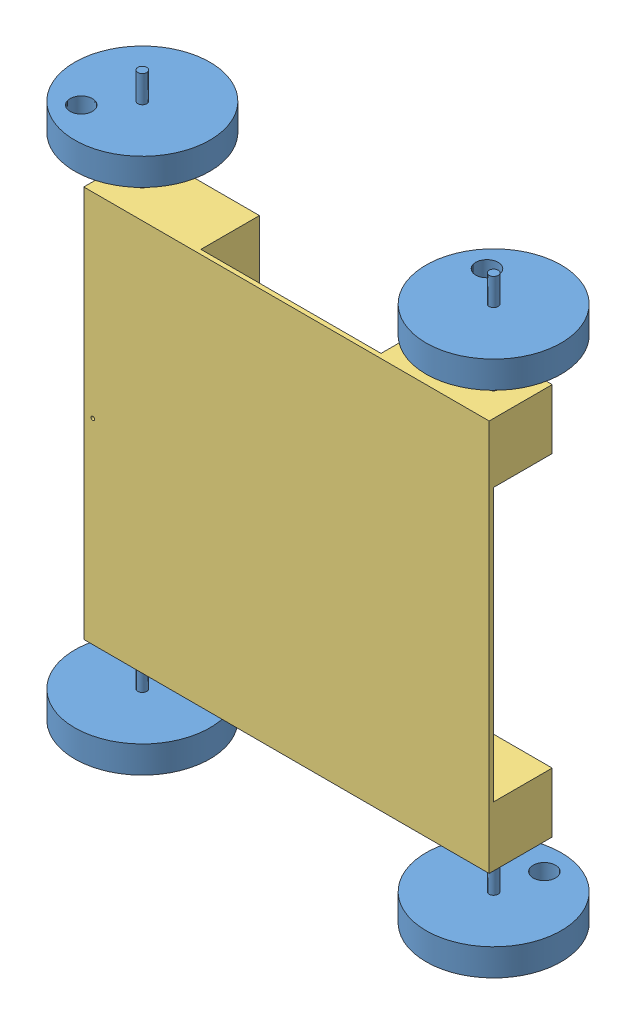
SolidWorks assembly lun, configuration 默认. Lengths in mm.
Overall size (593.07 655 203.07).
9 component instances, 3 part files, 16 mates.
Components (placement in the parent):
- lun-5: lun [默认] at (167.0466 -264.3091 -75) x (-0.881339 0 0.472485) z (0 -1 0) size (150 150 90)
- zhou-6: zhou [默认] at (167.0466 -234.3091 -75) x (1 0 0) z (0 1 0) size (10 10 30)
- zhou-7: zhou [默认] at (-222.9534 -234.3091 -75) x (-0.133084 0 -0.991105) z (0 1 0) size (10 10 30)
- zhou-8: zhou [默认] at (-222.9534 210.6909 -75) x (1 0 0) z (0 1 0) size (10 10 30)
- zhou-9: zhou [默认] at (167.0466 210.6909 -75) x (1 0 0) z (0 1 0) size (10 10 30)
- lun-6: lun [默认] at (167.0466 300.6909 -75) x (0 0 1) z (0 -1 0) size (150 150 90)
- lun-7: lun [默认] at (-222.9534 -264.3091 -75) x (-0.881339 0 0.472485) z (0 -1 0) size (150 150 90)
- SIMPLE DIPAN-2: SIMPLE DIPAN [默认] at (-27.9534 3.1909 -40) x (-1 0 0) z (0 0 -1) size (450 435 70)
- lun-8: lun [默认] at (-222.9534 300.6909 -75) x (1 0 0) z (0 -1 0) size (150 150 90)
Mates (geometry in assembly coordinates):
- 重合24: coincident: plane of zhou-7 through (-222.9534 -234.3091 -75) normal (0 -1 0); plane of lun-7 through (-222.9534 -234.3091 -75) normal (0 1 0)
- 同心17: concentric: cylinder of zhou-7 through (-222.9534 -204.3091 -75) axis (0 -1 0) radius 5; cylinder of lun-7 through (-222.9534 -234.3091 -75) axis (0 -1 0) radius 5
- 重合25: coincident: plane of lun-5 through (167.0466 -234.3091 -75) normal (0 1 0); plane of zhou-6 through (167.0466 -234.3091 -75) normal (0 -1 0)
- 同心18: concentric: cylinder of lun-5 through (167.0466 -234.3091 -75) axis (0 -1 0) radius 5; cylinder of zhou-6 through (167.0466 -204.3091 -75) axis (0 -1 0) radius 5
- 重合26: coincident: plane of zhou-6 through (167.0466 -204.3091 -75) normal (0 1 0); plane of SIMPLE DIPAN-2 through (167.0466 -204.3091 -75) normal (0 -1 0)
- 同心19: concentric: cylinder of zhou-6 through (167.0466 -204.3091 -75) axis (0 -1 0) radius 5; cylinder of SIMPLE DIPAN-2 through (167.0466 -204.3091 -75) axis (0 -1 0) radius 5
- 重合27: coincident: plane of zhou-7 through (-222.9534 -204.3091 -75) normal (0 1 0); plane of SIMPLE DIPAN-2 through (-222.9534 -204.3091 -75) normal (0 -1 0)
- 同心20: concentric: cylinder of zhou-7 through (-222.9534 -204.3091 -75) axis (0 -1 0) radius 5; cylinder of SIMPLE DIPAN-2 through (-222.9534 -204.3091 -75) axis (0 -1 0) radius 5
- 重合28: coincident: plane of zhou-8 through (-222.9534 210.6909 -75) normal (0 -1 0); plane of SIMPLE DIPAN-2 through (-222.9534 210.6909 -75) normal (0 1 0)
- 同心21: concentric: cylinder of zhou-8 through (-222.9534 240.6909 -75) axis (0 -1 0) radius 5; cylinder of SIMPLE DIPAN-2 through (-222.9534 210.6909 -75) axis (0 1 0) radius 5
- 重合29: coincident: plane of zhou-8 through (-222.9534 240.6909 -75) normal (0 1 0); plane of lun-8 through (-222.9534 240.6909 -75) normal (0 -1 0)
- 同心22: concentric: cylinder of zhou-8 through (-222.9534 240.6909 -75) axis (0 -1 0) radius 5; cylinder of lun-8 through (-222.9534 330.6909 -75) axis (0 -1 0) radius 5
- 重合30: coincident: plane of zhou-9 through (167.0466 210.6909 -75) normal (0 -1 0); plane of SIMPLE DIPAN-2 through (167.0466 210.6909 -75) normal (0 1 0)
- 同心23: concentric: cylinder of zhou-9 through (167.0466 240.6909 -75) axis (0 -1 0) radius 5; cylinder of SIMPLE DIPAN-2 through (167.0466 210.6909 -75) axis (0 1 0) radius 5
- 重合31: coincident: plane of zhou-9 through (167.0466 240.6909 -75) normal (0 1 0); plane of lun-6 through (167.0466 240.6909 -75) normal (0 -1 0)
- 同心24: concentric: cylinder of zhou-9 through (167.0466 240.6909 -75) axis (0 -1 0) radius 5; cylinder of lun-6 through (167.0466 330.6909 -75) axis (0 -1 0) radius 5
